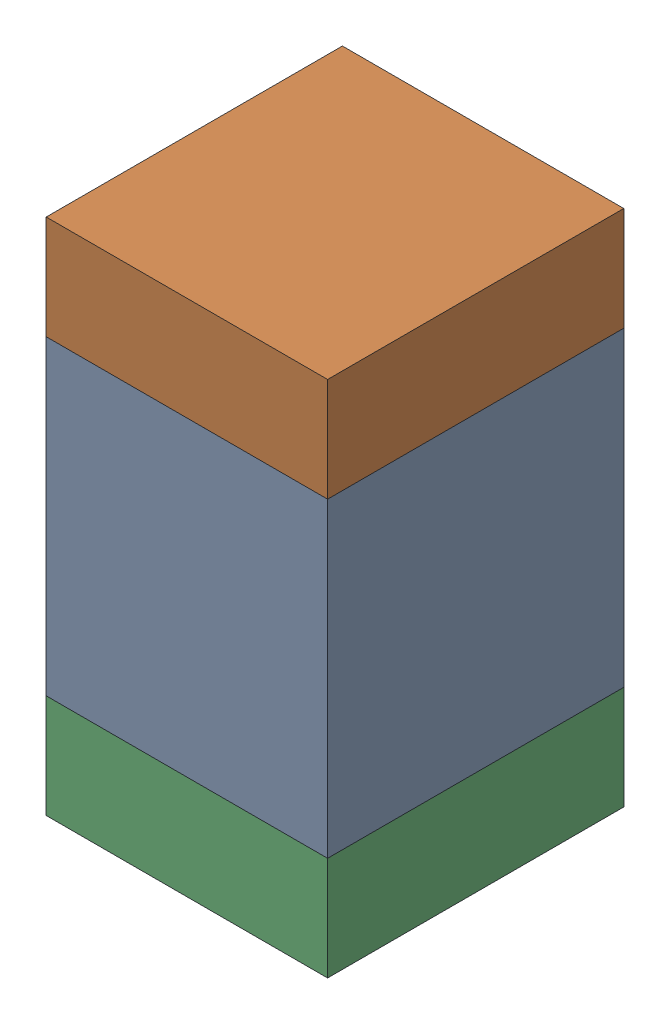
SolidWorks assembly C422PCB, configuration Default. Lengths in mm.
Overall size (0.95 1.75 1).
6 component instances, 2 part files, 0 mates.
Components (placement in the parent):
- 761616384-1: 761616384 [Default] at (134.6 103.8 -2.6638) size (0.95 1.05 1)
  - Extruded_5-1: Extruded_5 [Default] at origin size (0.95 1.05 1)
- 761616520-1: 761616520 [Default] at (134.6 104.5 -2.6638) size (0.95 0.35 1)
  - Extruded_6-1: Extruded_6 [Default] at origin size (0.95 0.35 1)
- 761616520-2: 761616520 [Default] at (134.6 103.1 -2.6638) size (0.95 0.35 1)
  - Extruded_6-1: Extruded_6 [Default] at origin size (0.95 0.35 1)
